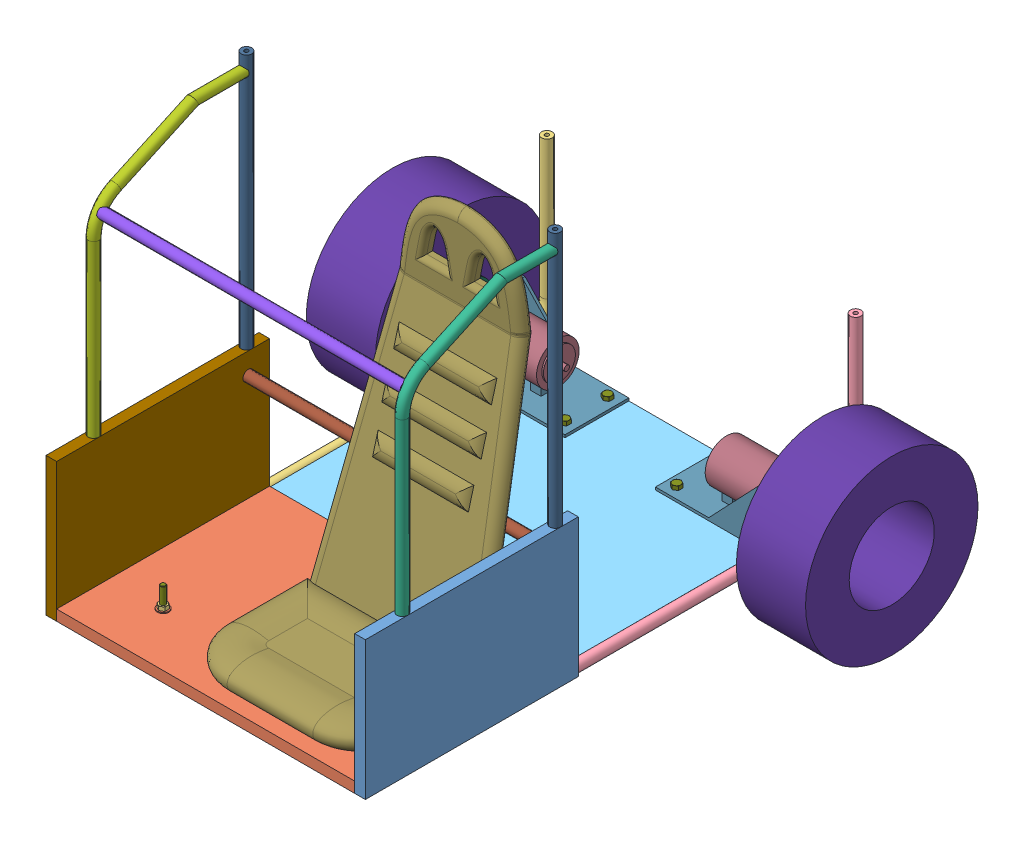
SolidWorks assembly MC (1), configuration Default. Lengths in mm.
Overall size (1191.26 1083.62 1343.85).
100 component instances, 21 part files, 123 mates.
Components (placement in the parent):
- SPL-1: SPL [Default] at (646.5449 178.7927 -996.551) size (25.4 330.2 508)
- BP-1: BP [Default] at (111.0665 -124.6065 -917.4807) size (711.2 25.4 508)
- BBR-2: BBR [Default] at (-77.3551 -47.0728 -1647.3326) x (-1 0 0) z (0 -1 0) size (25.4 687.13 407.73)
- BBL-1: BBL [Default] at (659.2449 -47.0728 -1647.3326) x (-1 0 0) z (0 -1 0) size (25.4 687.13 407.73)
- BC-1: BC [Default] at (357.2961 -116.9228 -1647.3326) x (-1 0 0) z (0 0 -1) size (723.9 12.7 609.6)
- FTL-1: FTL [Default] at (659.245 611.9935 -719.4116) x (0 -0.899323 -0.437285) z (-1 0 -0.000001) size (433.75 589.6 27.41)
- FTR-1: FTR [Default] at (-77.355 611.9935 -719.4116) x (0 -0.899323 -0.437285) z (-1 0 -0.000001) size (433.75 589.6 27.38)
- TC-1: TC [Default] at (652.8949 660.2535 -644.2461) x (0 -0.542655 -0.839955) z (-1 0 -0.000001) size (25.4 25.4 723.9)
- SPR-1: SPR [Default] at (-90.0551 178.7927 -996.551) size (25.4 330.2 508)
- BT-1: BT [Default] at (-77.3551 205.5935 -995.2506) x (0.000001 0 -1) z (1 0 0.000001) size (25.4 609.6 25.4)
- BT-2: BT [Default] at (659.2449 205.5935 -995.2506) x (0.000001 0 -1) z (1 0 0.000001) size (25.4 609.6 25.4)
- FB-1: FB [Default] at (-71.0051 154.7935 -986.9326) x (1 0 0) z (0 0.990518 0.137381) size (723.9 25.4 25.4)
- seat-1: seat [Default] at (418.0013 -99.2065 -848.8249) size (437.03 835.23 478.09)
- EA1-1: EA1 [Default] at (125.7912 -160.5315 -1631.3403) x (0 0 1) z (-1 0 0) size (411.48 411.48 487.68)
  - EB1-1: EB1 [Default] at (60.2077 126.1588 196.7963) size (101.6 101.6 238.25)
  - EP1-1: EP1 [Default] at (60.2077 56.3088 69.7963) x (0 0 1) z (-1 0 0) size (254 133.35 152.4)
  - EA2-1: EA2 [Default] at (45.9187 58.6487 138.5565) size (411.48 411.48 213.36)
    - EP2-1: EP2 [Default] at (14.289 67.5101 114.1198) size (127 127 48.26)
    - hex bolt_ai-1: hex bolt_ai [HBOLT 0.4375-20x1.375x1.125-N] at (-36.511 67.5101 106.0934) x (0 0 1) z (-0.866025 -0.5 0) size (42.95 18.33 15.88)
    - hex bolt_ai-2: hex bolt_ai [HBOLT 0.4375-20x1.375x1.125-N] at (14.289 118.3101 106.0934) x (0 0 1) z (0 -1 0) size (42.95 18.33 15.88)
    - hex bolt_ai-3: hex bolt_ai [HBOLT 0.4375-20x1.375x1.125-N] at (14.289 16.7101 106.0934) x (0 0 1) z (-0.866025 0.5 0) size (42.95 18.33 15.88)
    - hex bolt_ai-4: hex bolt_ai [HBOLT 0.4375-20x1.375x1.125-N] at (65.089 67.5101 106.0934) x (0 0 1) z (-0.866025 0.5 0) size (42.95 18.33 15.88)
    - EB2-1: EB2 [Default] at (14.289 67.5101 129.9948) x (-1 0 0) z (0 0 -1) size (411.48 411.48 165.1)
    - flat washer type a wide_ai-1: flat washer type a wide_ai [Preferred Wide FW 0.4375] at (-36.511 67.5101 132.103) x (0 0 1) z (-0.923728 -0.383049 0) size (2.11 31.75 31.75)
    - flat washer type a wide_ai-2: flat washer type a wide_ai [Preferred Wide FW 0.4375] at (14.289 118.3101 132.103) x (0 0 1) z (1 0 0) size (2.11 31.75 31.75)
    - flat washer type a wide_ai-3: flat washer type a wide_ai [Preferred Wide FW 0.4375] at (14.289 16.7101 132.103) x (0 0 1) z (1 0 0) size (2.11 31.75 31.75)
    - flat washer type a wide_ai-4: flat washer type a wide_ai [Preferred Wide FW 0.4375] at (65.089 67.5101 132.103) x (0 0 1) z (1 0 0) size (2.11 31.75 31.75)
    - hex thick nut_ai-1: hex thick nut_ai [HTNUT 0.4375-14-D-N] at (14.289 16.7101 143.8632) x (0.055202 -0.998475 0) z (0 0 1) size (17.48 20.18 11.76)
    - hex thick nut_ai-2: hex thick nut_ai [HTNUT 0.4375-14-D-N] at (-36.511 67.5101 143.8632) x (0.547044 -0.837104 0) z (0 0 1) size (17.48 20.18 11.76)
    - hex thick nut_ai-3: hex thick nut_ai [HTNUT 0.4375-14-D-N] at (65.089 67.5101 143.8632) x (-0.982324 -0.18719 0) z (0 0 1) size (17.48 20.18 11.76)
    - hex thick nut_ai-4: hex thick nut_ai [HTNUT 0.4375-14-D-N] at (14.289 118.3101 143.8632) x (0.055202 -0.998475 0) z (0 0 1) size (17.48 20.18 11.76)
  - hex bolt_ai-8: hex bolt_ai [HBOLT 0.3125-18x1.375x0.875-N] at (17.0277 169.3388 215.4653) x (0 0 -1) z (0 1 0) size (40.89 14.66 12.7)
  - hex bolt_ai-9: hex bolt_ai [HBOLT 0.3125-18x1.375x0.875-N] at (103.3877 169.3388 215.4653) x (0 0 -1) z (0.866025 -0.5 0) size (40.89 14.66 12.7)
  - hex bolt_ai-10: hex bolt_ai [HBOLT 0.3125-18x1.375x0.875-N] at (103.3877 82.9788 215.4653) x (0 0 -1) z (0.866025 0.5 0) size (40.89 14.66 12.7)
  - hex bolt_ai-11: hex bolt_ai [HBOLT 0.3125-18x1.375x0.875-N] at (17.0277 82.9788 215.4653) x (0 0 -1) z (-0.866025 -0.5 0) size (40.89 14.66 12.7)
  - flat washer type a narrow_ai-1: flat washer type a narrow_ai [Preferred Narrow FW 0.3125] at (17.0277 169.3388 190.4463) x (0 0 1) z (-1 0 0) size (1.65 17.48 17.48)
  - flat washer type a narrow_ai-2: flat washer type a narrow_ai [Preferred Narrow FW 0.3125] at (103.3877 82.9788 190.4463) x (0 0 1) z (-1 0 0) size (1.65 17.48 17.48)
  - flat washer type a narrow_ai-3: flat washer type a narrow_ai [Preferred Narrow FW 0.3125] at (17.0277 82.9788 188.7953) x (0 0 -1) z (1 0 0) size (1.65 17.48 17.48)
  - flat washer type a narrow_ai-4: flat washer type a narrow_ai [Preferred Narrow FW 0.3125] at (103.3877 169.3388 188.7953) x (0 0 -1) z (0.923728 0.383049 0) size (1.65 17.48 17.48)
  - hex thick nut_ai-1: hex thick nut_ai [HTNUT 0.3125-18-D-N] at (103.3877 169.3388 188.7953) x (0.866025 0.5 0) z (0 0 1) size (12.7 14.66 8.53)
  - hex thick nut_ai-2: hex thick nut_ai [HTNUT 0.3125-18-D-N] at (17.0277 82.9788 180.2609) x (-0.866025 0.5 0) z (0 0 -1) size (12.7 14.66 8.53)
  - hex thick nut_ai-3: hex thick nut_ai [HTNUT 0.3125-18-D-N] at (103.3877 82.9788 181.9119) x (-0.866025 -0.5 0) z (0 0 -1) size (12.7 14.66 8.53)
  - hex thick nut_ai-4: hex thick nut_ai [HTNUT 0.3125-18-D-N] at (17.0277 169.3388 180.2609) x (-0.866025 -0.5 0) z (0 0 -1) size (12.7 14.66 8.53)
- EA1-2: EA1 [Default] at (456.0986 -160.5315 -1510.9249) x (0 0 -1) z (1 0 0) size (411.48 411.48 487.68)
  - EB1-1: EB1 [Default] at (60.2077 126.1588 196.7963) size (101.6 101.6 238.25)
  - EP1-1: EP1 [Default] at (60.2077 56.3088 69.7963) x (0 0 1) z (-1 0 0) size (254 133.35 152.4)
  - EA2-1: EA2 [Default] at (45.9187 58.6487 138.5565) size (411.48 411.48 213.36)
    - EP2-1: EP2 [Default] at (14.289 67.5101 114.1198) size (127 127 48.26)
    - hex bolt_ai-1: hex bolt_ai [HBOLT 0.4375-20x1.375x1.125-N] at (-36.511 67.5101 106.0934) x (0 0 1) z (-0.866025 -0.5 0) size (42.95 18.33 15.88)
    - hex bolt_ai-2: hex bolt_ai [HBOLT 0.4375-20x1.375x1.125-N] at (14.289 118.3101 106.0934) x (0 0 1) z (0 -1 0) size (42.95 18.33 15.88)
    - hex bolt_ai-3: hex bolt_ai [HBOLT 0.4375-20x1.375x1.125-N] at (14.289 16.7101 106.0934) x (0 0 1) z (-0.866025 0.5 0) size (42.95 18.33 15.88)
    - hex bolt_ai-4: hex bolt_ai [HBOLT 0.4375-20x1.375x1.125-N] at (65.089 67.5101 106.0934) x (0 0 1) z (-0.866025 0.5 0) size (42.95 18.33 15.88)
    - EB2-1: EB2 [Default] at (14.289 67.5101 129.9948) x (-1 0 0) z (0 0 -1) size (411.48 411.48 165.1)
    - flat washer type a wide_ai-1: flat washer type a wide_ai [Preferred Wide FW 0.4375] at (-36.511 67.5101 132.103) x (0 0 1) z (-0.923728 -0.383049 0) size (2.11 31.75 31.75)
    - flat washer type a wide_ai-2: flat washer type a wide_ai [Preferred Wide FW 0.4375] at (14.289 118.3101 132.103) x (0 0 1) z (1 0 0) size (2.11 31.75 31.75)
    - flat washer type a wide_ai-3: flat washer type a wide_ai [Preferred Wide FW 0.4375] at (14.289 16.7101 132.103) x (0 0 1) z (1 0 0) size (2.11 31.75 31.75)
    - flat washer type a wide_ai-4: flat washer type a wide_ai [Preferred Wide FW 0.4375] at (65.089 67.5101 132.103) x (0 0 1) z (1 0 0) size (2.11 31.75 31.75)
    - hex thick nut_ai-1: hex thick nut_ai [HTNUT 0.4375-14-D-N] at (14.289 16.7101 143.8632) x (0.055202 -0.998475 0) z (0 0 1) size (17.48 20.18 11.76)
    - hex thick nut_ai-2: hex thick nut_ai [HTNUT 0.4375-14-D-N] at (-36.511 67.5101 143.8632) x (0.547044 -0.837104 0) z (0 0 1) size (17.48 20.18 11.76)
    - hex thick nut_ai-3: hex thick nut_ai [HTNUT 0.4375-14-D-N] at (65.089 67.5101 143.8632) x (-0.982324 -0.18719 0) z (0 0 1) size (17.48 20.18 11.76)
    - hex thick nut_ai-4: hex thick nut_ai [HTNUT 0.4375-14-D-N] at (14.289 118.3101 143.8632) x (0.055202 -0.998475 0) z (0 0 1) size (17.48 20.18 11.76)
  - hex bolt_ai-8: hex bolt_ai [HBOLT 0.3125-18x1.375x0.875-N] at (17.0277 169.3388 215.4653) x (0 0 -1) z (0 1 0) size (40.89 14.66 12.7)
  - hex bolt_ai-9: hex bolt_ai [HBOLT 0.3125-18x1.375x0.875-N] at (103.3877 169.3388 215.4653) x (0 0 -1) z (0.866025 -0.5 0) size (40.89 14.66 12.7)
  - hex bolt_ai-10: hex bolt_ai [HBOLT 0.3125-18x1.375x0.875-N] at (103.3877 82.9788 215.4653) x (0 0 -1) z (0.866025 0.5 0) size (40.89 14.66 12.7)
  - hex bolt_ai-11: hex bolt_ai [HBOLT 0.3125-18x1.375x0.875-N] at (17.0277 82.9788 215.4653) x (0 0 -1) z (-0.866025 -0.5 0) size (40.89 14.66 12.7)
  - flat washer type a narrow_ai-1: flat washer type a narrow_ai [Preferred Narrow FW 0.3125] at (17.0277 169.3388 190.4463) x (0 0 1) z (-1 0 0) size (1.65 17.48 17.48)
  - flat washer type a narrow_ai-2: flat washer type a narrow_ai [Preferred Narrow FW 0.3125] at (103.3877 82.9788 190.4463) x (0 0 1) z (-1 0 0) size (1.65 17.48 17.48)
  - flat washer type a narrow_ai-3: flat washer type a narrow_ai [Preferred Narrow FW 0.3125] at (17.0277 82.9788 188.7953) x (0 0 -1) z (1 0 0) size (1.65 17.48 17.48)
  - flat washer type a narrow_ai-4: flat washer type a narrow_ai [Preferred Narrow FW 0.3125] at (103.3877 169.3388 188.7953) x (0 0 -1) z (0.923728 0.383049 0) size (1.65 17.48 17.48)
  - hex thick nut_ai-1: hex thick nut_ai [HTNUT 0.3125-18-D-N] at (103.3877 169.3388 188.7953) x (0.866025 0.5 0) z (0 0 1) size (12.7 14.66 8.53)
  - hex thick nut_ai-2: hex thick nut_ai [HTNUT 0.3125-18-D-N] at (17.0277 82.9788 180.2609) x (-0.866025 0.5 0) z (0 0 -1) size (12.7 14.66 8.53)
  - hex thick nut_ai-3: hex thick nut_ai [HTNUT 0.3125-18-D-N] at (103.3877 82.9788 181.9119) x (-0.866025 -0.5 0) z (0 0 -1) size (12.7 14.66 8.53)
  - hex thick nut_ai-4: hex thick nut_ai [HTNUT 0.3125-18-D-N] at (17.0277 169.3388 180.2609) x (-0.866025 -0.5 0) z (0 0 -1) size (12.7 14.66 8.53)
- hex bolt_ai-1: hex bolt_ai [HBOLT 0.5000-13x1.375x1.25-N] at (157.5949 -88.6272 -1621.9326) x (0 -1 0) z (-1 0 0) size (44.17 22 19.05)
- hex bolt_ai-2: hex bolt_ai [HBOLT 0.5000-13x1.375x1.25-N] at (157.5949 -88.6272 -1520.3326) x (0 -1 0) z (0.5 0 -0.866025) size (44.17 22 19.05)
- hex bolt_ai-3: hex bolt_ai [HBOLT 0.5000-13x1.375x1.25-N] at (424.2949 -88.6272 -1520.3326) x (0 -1 0) z (1 0 0) size (44.17 22 19.05)
- hex bolt_ai-4: hex bolt_ai [HBOLT 0.5000-13x1.375x1.25-N] at (602.0949 -88.6272 -1621.9326) x (0 -1 0) z (-0.5 0 -0.866025) size (44.17 22 19.05)
- hex bolt_ai-5: hex bolt_ai [HBOLT 0.5000-13x1.375x1.25-N] at (424.2949 -88.6272 -1621.9326) x (0 -1 0) z (0.5 0 -0.866025) size (44.17 22 19.05)
- hex bolt_ai-6: hex bolt_ai [HBOLT 0.5000-13x1.375x1.25-N] at (602.0949 -88.6272 -1520.3326) x (0 -1 0) z (-0.5 0 0.866025) size (44.17 22 19.05)
- hex bolt_ai-7: hex bolt_ai [HBOLT 0.5000-13x1.375x1.25-N] at (-20.2051 -88.6272 -1621.9326) x (0 -1 0) z (-1 0 0) size (44.17 22 19.05)
- hex bolt_ai-8: hex bolt_ai [HBOLT 0.5000-13x1.375x1.25-N] at (-20.2051 -88.6272 -1520.3326) x (0 -1 0) z (1 0 0) size (44.17 22 19.05)
- flat washer type a wide_ai-1: flat washer type a wide_ai [Preferred Wide FW 0.5] at (157.5949 -119.6914 -1520.3326) x (0 -1 0) z (0.546944 0 -0.837169) size (2.77 34.92 34.92)
- flat washer type a wide_ai-2: flat washer type a wide_ai [Preferred Wide FW 0.5] at (157.5949 -119.6914 -1621.9326) x (0 -1 0) z (0.967366 0 0.253384) size (2.77 34.92 34.92)
- flat washer type a wide_ai-3: flat washer type a wide_ai [Preferred Wide FW 0.5] at (424.2949 -119.6914 -1621.9326) x (0 -1 0) z (-0.558017 0 -0.829829) size (2.77 34.92 34.92)
- flat washer type a wide_ai-4: flat washer type a wide_ai [Preferred Wide FW 0.5] at (-20.2051 -119.6914 -1520.3326) x (0 -1 0) z (0.590888 0 -0.806754) size (2.77 34.92 34.92)
- flat washer type a wide_ai-5: flat washer type a wide_ai [Preferred Wide FW 0.5] at (602.0949 -119.6914 -1520.3326) x (0 -1 0) z (0.610265 0 -0.792197) size (2.77 34.92 34.92)
- flat washer type a wide_ai-6: flat washer type a wide_ai [Preferred Wide FW 0.5] at (424.2949 -119.6914 -1520.3326) x (0 -1 0) z (0.837672 0 -0.546174) size (2.77 34.92 34.92)
- flat washer type a wide_ai-7: flat washer type a wide_ai [Preferred Wide FW 0.5] at (602.0949 -119.6914 -1621.9326) x (0 -1 0) z (0.97172 0 -0.236136) size (2.77 34.92 34.92)
- flat washer type a wide_ai-8: flat washer type a wide_ai [Preferred Wide FW 0.5] at (-20.2051 -119.6914 -1621.9326) x (0 -1 0) z (0.345214 0 -0.938524) size (2.77 34.92 34.92)
- hex nut_ai-1: hex nut_ai [HNUT 0.5000-13-D-N] at (157.5949 -131.0706 -1520.3326) x (-0.5 0 -0.866025) z (0 -1 0) size (19.05 22 11.38)
- hex nut_ai-2: hex nut_ai [HNUT 0.5000-13-D-N] at (-20.2051 -131.0706 -1621.9326) x (-0.866025 0 -0.5) z (0 -1 0) size (19.05 22 11.38)
- hex nut_ai-3: hex nut_ai [HNUT 0.5000-13-D-N] at (-20.2051 -131.0706 -1520.3326) x (0 0 -1) z (0 -1 0) size (19.05 22 11.38)
- hex nut_ai-4: hex nut_ai [HNUT 0.5000-13-D-N] at (157.5949 -131.0706 -1621.9326) x (0 0 -1) z (0 -1 0) size (19.05 22 11.38)
- hex nut_ai-5: hex nut_ai [HNUT 0.5000-13-D-N] at (424.2949 -131.0706 -1520.3326) x (0 0 1) z (0 -1 0) size (19.05 22 11.38)
- hex nut_ai-6: hex nut_ai [HNUT 0.5000-13-D-N] at (424.2949 -131.0706 -1621.9326) x (-0.866025 0 0.5) z (0 -1 0) size (19.05 22 11.38)
- hex nut_ai-8: hex nut_ai [HNUT 0.5000-13-D-N] at (602.0949 -131.0706 -1520.3326) x (-0.866025 0 -0.5) z (0 -1 0) size (19.05 22 11.38)
- hex nut_ai-9: hex nut_ai [HNUT 0.5000-13-D-N] at (602.0949 -131.0706 -1621.9326) x (-0.866025 0 -0.5) z (0 -1 0) size (19.05 22 11.38)
- hex bolt_ai-11: hex bolt_ai [HBOLT 0.5000-13x3x1.25-N] at (62.3449 -133.8521 -656.7326) x (0 1 0) z (-0.5 0 0.866025) size (85.45 22 19.05)
- flat washer type a narrow_ai-1: flat washer type a narrow_ai [Preferred Narrow FW 0.5] at (62.3449 -99.2065 -656.7326) x (0 -1 0) z (0 0 1) size (2.41 26.97 26.97)
- hex nut_ai-10: hex nut_ai [HNUT 0.5000-13-D-N] at (62.3449 -87.8273 -656.7326) x (1 0 0) z (0 1 0) size (19.05 22 11.38)
Mates (geometry in assembly coordinates):
- Coincident29: coincident: plane of SPL-1 through (671.9449 205.5935 -1037.7326) normal (0 0 -1); plane of BBL-1 through (659.2449 -111.9065 -1037.7326) normal (0 0 1)
- Tangent6: tangent: plane of SPL-1 through (671.9449 178.7927 -996.551) normal (1 0 0); cylinder of BBL-1 through (659.2449 -111.9065 -1037.7326) axis (0 0 -1) radius 12.7
- Tangent7: tangent: plane of SPL-1 through (671.9449 -124.6065 -529.7326) normal (0 -1 0); cylinder of BBL-1 through (659.2449 -111.9065 -1037.7326) axis (0 0 -1) radius 12.7
- Coincident32: coincident: plane of BP-1 through (-64.6551 -99.2065 -1037.7326) normal (0 0 -1); plane of BC-1 through (652.8949 -104.2228 -1037.7326) normal (0 0 1)
- Coincident34: coincident: plane of BBR-2 through (-71.0051 -104.2228 -1037.7326) normal (0 -1 0); plane of BC-1 through (357.2961 -104.2228 -1647.3326) normal (0 1 0)
- Tangent9: tangent: plane of SPL-1 through (671.9449 178.7927 -996.551) normal (1 0 0); cylinder of BBL-1 through (659.2449 283.1272 -1712.1664) axis (0 -1 0) radius 12.7
- Tangent10: tangent: plane of SPL-1 through (671.9449 178.7927 -996.551) normal (1 0 0); cylinder of FTL-1 through (659.2449 205.5935 -630.5357) axis (0 1 0) radius 12.7
- Coincident46: coincident: plane of SPL-1 through (646.5449 178.7927 -996.551) normal (-1 0 0); plane of BP-1 through (646.5449 -99.2065 -1037.7326) normal (1 0 0)
- Coincident48: coincident: plane of SPL-1 through (671.9449 -124.6065 -529.7326) normal (0 -1 0); plane of BP-1 through (111.0665 -124.6065 -917.4807) normal (0 -1 0)
- Parallel1: parallel: plane of BP-1 through (111.0665 -124.6065 -917.4807) normal (0 -1 0); plane of BC-1 through (357.2961 -116.9228 -1647.3326) normal (0 -1 0)
- Distance1: distance = 101.6 mm: cylinder of FTL-1 through (659.2449 205.5935 -630.5357) axis (0 1 0) radius 12.7; line of SPL-1 through (646.5449 205.5935 -529.7326) axis (0 -1 0)
- Coincident53: coincident: plane of FTR-1 through (-71.0051 660.2535 -644.2465) normal (1 0 0.000001); plane of TC-1 through (-71.0051 660.2535 -644.2465) normal (-1 0 -0.000001)
- Coincident55: coincident: plane of FTL-1 through (652.8949 660.2535 -644.2465) normal (-1 0 -0.000001); circle of TC-1
- Coincident56: coincident: plane of SPL-1 through (671.9449 205.5935 -1037.7326) normal (0 0 -1); plane of BP-1 through (-64.6551 -99.2065 -1037.7326) normal (0 0 -1)
- Coincident60: coincident: plane of SPL-1 through (671.9449 205.5935 -1037.7326) normal (0 0 -1); plane of BP-1 through (-64.6551 -99.2065 -1037.7326) normal (0 0 -1)
- Coincident61: coincident: plane of BP-1 through (111.0665 -124.6065 -917.4807) normal (0 -1 0); plane of SPR-1 through (-64.6551 -124.6065 -529.7326) normal (0 -1 0)
- Coincident62: coincident: plane of BP-1 through (-64.6551 -99.2065 -1037.7326) normal (-1 0 0); plane of SPR-1 through (-64.6551 178.7927 -996.551) normal (1 0 0)
- Coincident63: coincident: plane of BP-1 through (-64.6551 -99.2065 -1037.7326) normal (0 0 -1); plane of SPR-1 through (-64.6551 205.5935 -1037.7326) normal (0 0 -1)
- Tangent20: tangent: cylinder of BBR-2 through (-77.3551 -111.9065 -1037.7326) axis (0 0 -1) radius 12.7; plane of SPR-1 through (-90.0551 178.7927 -996.551) normal (-1 0 0)
- Tangent21: tangent: cylinder of BBR-2 through (-77.3551 -111.9065 -1037.7326) axis (0 0 -1) radius 12.7; plane of SPR-1 through (-64.6551 -124.6065 -529.7326) normal (0 -1 0)
- Tangent24: tangent: cylinder of BBR-2 through (-77.3551 -111.9065 -1037.7326) axis (0 0 -1) radius 12.7; plane of SPR-1 through (-64.6551 -124.6065 -529.7326) normal (0 -1 0)
- Coincident67: coincident: plane of BBR-2 through (-77.3551 -111.9065 -1037.7326) normal (0 0 1); plane of SPR-1 through (-64.6551 205.5935 -1037.7326) normal (0 0 -1)
- Parallel2: parallel: cylinder of BBR-2 through (-77.3551 283.1272 -1712.1664) axis (0 -1 0) radius 12.7; line of SPR-1 through (-64.6551 -124.6065 -1037.7326) axis (0 1 0)
- Coincident69: coincident: plane of SPR-1 through (-64.6551 205.5935 -529.7326) normal (0 1 0); plane of BT-1 through (-77.3551 205.5935 -995.2506) normal (0 -1 0)
- Coincident70: coincident: plane of SPL-1 through (671.9449 205.5935 -529.7326) normal (0 1 0); plane of BT-2 through (659.2449 205.5935 -995.2506) normal (0 -1 0)
- Coincident73: coincident: plane of SPR-1 through (-64.6551 205.5935 -529.7326) normal (0 1 0); plane of BT-1 through (-77.3551 205.5935 -995.2506) normal (0 -1 0)
- Tangent34: tangent: plane of SPR-1 through (-90.0551 178.7927 -996.551) normal (-1 0 0); cylinder of BT-1 through (-77.3551 815.1935 -995.2506) axis (0 -1 0) radius 12.7
- Tangent36: tangent: plane of SPL-1 through (671.9449 178.7927 -996.551) normal (1 0 0); cylinder of BT-2 through (659.2449 815.1935 -995.2506) axis (0 -1 0) radius 12.7
- Coincident74: coincident: plane of SPL-1 through (652.8949 154.7935 -986.9326) normal (-1 0 0); plane of FB-1 through (652.8949 154.7935 -986.9326) normal (1 0 0)
- Coincident75: coincident: plane of SPR-1 through (-71.0051 154.7935 -986.9326) normal (1 0 0); plane of FB-1 through (-71.0051 154.7935 -986.9326) normal (-1 0 0)
- Concentric1: concentric: circle of SPL-1; circle of FB-1
- Coincident77: coincident: plane of SPR-1 through (-71.0051 154.7935 -986.9326) normal (1 0 0); circle of FB-1
- Concentric2: concentric: circle of SPR-1; circle of FB-1
- Coincident81: coincident: plane of BP-1 through (111.0665 -99.2065 -917.4807) normal (0 1 0); plane of seat-1 through (633.9013 -99.2065 -833.6366) normal (0 -1 0)
- Coincident82: coincident: plane of FTR-1 through (-77.3551 205.5935 -630.5357) normal (0 -1 0); plane of SPR-1 through (-64.6551 205.5935 -529.7326) normal (0 1 0)
- Coincident83: coincident: plane of SPL-1 through (671.9449 205.5935 -529.7326) normal (0 1 0); plane of FTL-1 through (659.2449 205.5935 -630.5357) normal (0 -1 0)
- Coincident84: coincident: plane of BC-1 through (357.2961 -104.2228 -1647.3326) normal (0 1 0); plane of EA1-1/EP1-1 through (55.9949 -104.2228 -1571.1326) normal (0 -1 0)
- Concentric3: concentric: circle of BC-1; circle of EA1-1/EP1-1
- Concentric5: concentric: circle of BC-1; circle of EA1-1/EP1-1
- Coincident89: coincident: plane of BC-1 through (357.2961 -104.2228 -1647.3326) normal (0 1 0); plane of EA1-2/EP1-1 through (525.8949 -104.2228 -1571.1326) normal (0 -1 0)
- Concentric6: concentric: circle of BC-1; circle of EA1-2/EP1-1
- Concentric7: concentric: circle of BC-1; circle of EA1-2/EP1-1
- Concentric8: concentric: cylinder of EA1-1/EP1-1 through (157.5949 -123.2728 -1520.3326) axis (0 1 0) radius 6.35; cylinder of hex bolt_ai-2 through (157.5949 -88.6272 -1520.3326) axis (0 1 0) radius 6.35
- Coincident92: coincident: plane of EA1-1/EP1-1 through (55.9949 -97.8728 -1571.1326) normal (0 1 0); plane of hex bolt_ai-2 through (148.0699 -97.8728 -1525.8319) normal (0 -1 0)
- Parallel8: parallel: plane of EA1-1/EP1-1 through (182.9949 -97.8728 -1494.9326) normal (1 0 0); plane of hex bolt_ai-2 through (167.1199 -97.8728 -1514.8333) normal (1 0 0)
- Concentric9: concentric: cylinder of hex bolt_ai-2 through (157.5949 -88.6272 -1520.3326) axis (0 1 0) radius 6.35; cylinder of flat washer type a wide_ai-1 through (157.5949 -84.7664 -1520.3326) axis (0 1 0) radius 7.1374
- Coincident94: coincident: plane of BC-1 through (357.2961 -116.9228 -1647.3326) normal (0 -1 0); plane of flat washer type a wide_ai-1 through (142.9759 -116.9228 -1529.8836) normal (0 1 0)
- Concentric10: concentric: cylinder of hex bolt_ai-2 through (157.5949 -88.6272 -1520.3326) axis (0 1 0) radius 6.35; cylinder of hex nut_ai-1 through (157.5949 -119.6914 -1520.3326) axis (0 -1 0) radius 5.3581
- Coincident95: coincident: plane of flat washer type a wide_ai-1 through (151.6197 -119.6914 -1524.2364) normal (0 -1 0); plane of hex nut_ai-1 through (167.1199 -119.6914 -1525.8319) normal (0 1 0)
- Parallel9: parallel: plane of EA1-1/EP1-1 through (182.9949 -97.8728 -1494.9326) normal (1 0 0); plane of hex nut_ai-1 through (167.1199 -119.6914 -1525.8319) normal (1 0 0)
- Concentric11: concentric: cylinder of EA1-1/EP1-1 through (157.5949 -123.2728 -1621.9326) axis (0 1 0) radius 6.35; cylinder of hex bolt_ai-1 through (157.5949 -88.6272 -1621.9326) axis (0 1 0) radius 6.35
- Coincident97: coincident: plane of EA1-1/EP1-1 through (55.9949 -97.8728 -1571.1326) normal (0 1 0); plane of hex bolt_ai-1 through (157.5949 -97.8728 -1610.9341) normal (0 -1 0)
- Parallel10: parallel: plane of EA1-1/EP1-1 through (182.9949 -97.8728 -1494.9326) normal (1 0 0); plane of hex bolt_ai-1 through (167.1199 -97.8728 -1616.4333) normal (1 0 0)
- Concentric12: concentric: cylinder of EA1-2/EP1-1 through (424.2949 -123.2728 -1520.3326) axis (0 1 0) radius 6.35; cylinder of hex bolt_ai-3 through (424.2949 -88.6272 -1520.3326) axis (0 1 0) radius 6.35
- Coincident99: coincident: plane of EA1-2/EP1-1 through (525.8949 -97.8728 -1571.1326) normal (0 1 0); plane of hex bolt_ai-3 through (424.2949 -97.8728 -1531.3311) normal (0 -1 0)
- Parallel11: parallel: plane of EA1-2/EP1-1 through (398.8949 -97.8728 -1647.3326) normal (-1 0 0); plane of hex bolt_ai-3 through (433.8199 -97.8728 -1525.8319) normal (1 0 0)
- Concentric13: concentric: cylinder of BC-1 through (424.2949 -116.9228 -1621.9326) axis (0 1 0) radius 6.35; cylinder of hex bolt_ai-5 through (424.2949 -88.6272 -1621.9326) axis (0 1 0) radius 6.35
- Coincident101: coincident: plane of EA1-2/EP1-1 through (525.8949 -97.8728 -1571.1326) normal (0 1 0); plane of hex bolt_ai-5 through (414.7699 -97.8728 -1627.4319) normal (0 -1 0)
- Concentric14: concentric: cylinder of EA1-1/EP1-1 through (-20.2051 -123.2728 -1520.3326) axis (0 1 0) radius 6.35; cylinder of hex bolt_ai-8 through (-20.2051 -88.6272 -1520.3326) axis (0 1 0) radius 6.35
- Coincident102: coincident: plane of EA1-1/EP1-1 through (55.9949 -97.8728 -1571.1326) normal (0 1 0); plane of hex bolt_ai-8 through (-20.2051 -97.8728 -1531.3311) normal (0 -1 0)
- Parallel12: parallel: plane of EA1-1/EP1-1 through (182.9949 -97.8728 -1494.9326) normal (1 0 0); plane of hex bolt_ai-8 through (-10.6801 -97.8728 -1525.8319) normal (1 0 0)
- Concentric15: concentric: cylinder of EA1-1/EP1-1 through (-20.2051 -123.2728 -1621.9326) axis (0 1 0) radius 6.35; cylinder of hex bolt_ai-7 through (-20.2051 -88.6272 -1621.9326) axis (0 1 0) radius 6.35
- Coincident104: coincident: plane of EA1-1/EP1-1 through (55.9949 -97.8728 -1571.1326) normal (0 1 0); plane of hex bolt_ai-7 through (-20.2051 -97.8728 -1610.9341) normal (0 -1 0)
- Parallel13: parallel: plane of EA1-1/EP1-1 through (182.9949 -97.8728 -1494.9326) normal (1 0 0); plane of hex bolt_ai-7 through (-10.6801 -97.8728 -1616.4333) normal (1 0 0)
- Concentric16: concentric: cylinder of EA1-2/EP1-1 through (602.0949 -123.2728 -1621.9326) axis (0 1 0) radius 6.35; cylinder of hex bolt_ai-4 through (602.0949 -88.6272 -1621.9326) axis (0 1 0) radius 6.35
- Coincident106: coincident: plane of EA1-2/EP1-1 through (525.8949 -97.8728 -1571.1326) normal (0 1 0); plane of hex bolt_ai-4 through (592.5699 -97.8728 -1616.4333) normal (0 -1 0)
- Parallel14: parallel: plane of EA1-2/EP1-1 through (398.8949 -97.8728 -1647.3326) normal (-1 0 0); plane of hex bolt_ai-4 through (592.5699 -97.8728 -1616.4333) normal (-1 0 0)
- Concentric17: concentric: cylinder of EA1-2/EP1-1 through (602.0949 -123.2728 -1520.3326) axis (0 1 0) radius 6.35; cylinder of hex bolt_ai-6 through (602.0949 -88.6272 -1520.3326) axis (0 1 0) radius 6.35
- Coincident108: coincident: plane of EA1-2/EP1-1 through (525.8949 -97.8728 -1571.1326) normal (0 1 0); plane of hex bolt_ai-6 through (611.6199 -97.8728 -1514.8333) normal (0 -1 0)
- Parallel15: parallel: plane of EA1-2/EP1-1 through (398.8949 -97.8728 -1647.3326) normal (-1 0 0); plane of hex bolt_ai-6 through (592.5699 -97.8728 -1525.8319) normal (-1 0 0)
- Parallel16: parallel: plane of EA1-2/EP1-1 through (398.8949 -97.8728 -1647.3326) normal (-1 0 0); plane of hex bolt_ai-5 through (414.7699 -97.8728 -1616.4333) normal (-1 0 0)
- Concentric18: concentric: cylinder of hex bolt_ai-1 through (157.5949 -88.6272 -1621.9326) axis (0 1 0) radius 6.35; cylinder of flat washer type a wide_ai-2 through (157.5949 -84.7664 -1621.9326) axis (0 1 0) radius 7.1374
- Concentric19: concentric: cylinder of hex bolt_ai-8 through (-20.2051 -88.6272 -1520.3326) axis (0 1 0) radius 6.35; cylinder of flat washer type a wide_ai-4 through (-20.2051 -84.7664 -1520.3326) axis (0 1 0) radius 7.1374
- Concentric20: concentric: cylinder of hex bolt_ai-7 through (-20.2051 -88.6272 -1621.9326) axis (0 1 0) radius 6.35; cylinder of flat washer type a wide_ai-8 through (-20.2051 -84.7664 -1621.9326) axis (0 1 0) radius 7.1374
- Concentric21: concentric: cylinder of hex bolt_ai-5 through (424.2949 -88.6272 -1621.9326) axis (0 1 0) radius 6.35; cylinder of flat washer type a wide_ai-3 through (424.2949 -84.7664 -1621.9326) axis (0 1 0) radius 7.1374
- Concentric22: concentric: cylinder of hex bolt_ai-3 through (424.2949 -88.6272 -1520.3326) axis (0 1 0) radius 6.35; cylinder of flat washer type a wide_ai-6 through (424.2949 -84.7664 -1520.3326) axis (0 1 0) radius 7.1374
- Concentric23: concentric: cylinder of hex bolt_ai-6 through (602.0949 -88.6272 -1520.3326) axis (0 1 0) radius 6.35; cylinder of flat washer type a wide_ai-5 through (602.0949 -84.7664 -1520.3326) axis (0 1 0) radius 7.1374
- Concentric24: concentric: cylinder of hex bolt_ai-4 through (602.0949 -88.6272 -1621.9326) axis (0 1 0) radius 6.35; cylinder of flat washer type a wide_ai-7 through (602.0949 -84.7664 -1621.9326) axis (0 1 0) radius 7.1374
- Coincident111: coincident: plane of BC-1 through (357.2961 -116.9228 -1647.3326) normal (0 -1 0); plane of flat washer type a wide_ai-5 through (588.2612 -116.9228 -1530.9894) normal (0 1 0)
- Coincident112: coincident: plane of BC-1 through (357.2961 -116.9228 -1647.3326) normal (0 -1 0); plane of flat washer type a wide_ai-7 through (597.9714 -116.9228 -1638.9013) normal (0 1 0)
- Coincident113: coincident: plane of BC-1 through (357.2961 -116.9228 -1647.3326) normal (0 -1 0); plane of flat washer type a wide_ai-6 through (414.7574 -116.9228 -1534.9604) normal (0 1 0)
- Coincident114: coincident: plane of BC-1 through (357.2961 -116.9228 -1647.3326) normal (0 -1 0); plane of flat washer type a wide_ai-3 through (409.804 -116.9228 -1612.1882) normal (0 1 0)
- Coincident115: coincident: plane of BC-1 through (357.2961 -116.9228 -1647.3326) normal (0 -1 0); plane of flat washer type a wide_ai-2 through (162.0196 -116.9228 -1638.8252) normal (0 1 0)
- Coincident116: coincident: plane of BC-1 through (357.2961 -116.9228 -1647.3326) normal (0 -1 0); plane of flat washer type a wide_ai-4 through (-34.293 -116.9228 -1530.651) normal (0 1 0)
- Coincident117: coincident: plane of BC-1 through (357.2961 -116.9228 -1647.3326) normal (0 -1 0); plane of flat washer type a wide_ai-8 through (-36.5941 -116.9228 -1627.9609) normal (0 1 0)
- Concentric26: concentric: cylinder of hex bolt_ai-7 through (-20.2051 -88.6272 -1621.9326) axis (0 1 0) radius 6.35; cylinder of hex nut_ai-2 through (-20.2051 -119.6914 -1621.9326) axis (0 -1 0) radius 5.3581
- Concentric27: concentric: cylinder of hex bolt_ai-8 through (-20.2051 -88.6272 -1520.3326) axis (0 1 0) radius 6.35; cylinder of hex nut_ai-3 through (-20.2051 -119.6914 -1520.3326) axis (0 -1 0) radius 5.3581
- Concentric28: concentric: cylinder of hex bolt_ai-1 through (157.5949 -88.6272 -1621.9326) axis (0 1 0) radius 6.35; cylinder of hex nut_ai-4 through (157.5949 -119.6914 -1621.9326) axis (0 -1 0) radius 5.3581
- Concentric29: concentric: cylinder of hex bolt_ai-5 through (424.2949 -88.6272 -1621.9326) axis (0 1 0) radius 6.35; cylinder of hex nut_ai-6 through (424.2949 -119.6914 -1621.9326) axis (0 -1 0) radius 5.3581
- Concentric30: concentric: cylinder of hex bolt_ai-3 through (424.2949 -88.6272 -1520.3326) axis (0 1 0) radius 6.35; cylinder of hex nut_ai-5 through (424.2949 -119.6914 -1520.3326) axis (0 -1 0) radius 5.3581
- Concentric31: concentric: cylinder of hex bolt_ai-6 through (602.0949 -88.6272 -1520.3326) axis (0 1 0) radius 6.35; cylinder of hex nut_ai-8 through (602.0949 -119.6914 -1520.3326) axis (0 -1 0) radius 5.3581
- Concentric32: concentric: cylinder of hex bolt_ai-4 through (602.0949 -88.6272 -1621.9326) axis (0 1 0) radius 6.35; cylinder of hex nut_ai-9 through (602.0949 -119.6914 -1621.9326) axis (0 -1 0) radius 5.3581
- Coincident119: coincident: plane of flat washer type a wide_ai-2 through (159.4034 -119.6914 -1628.8371) normal (0 -1 0); plane of hex nut_ai-4 through (168.5934 -119.6914 -1621.9326) normal (0 1 0)
- Parallel18: parallel: plane of BC-1 through (652.8949 -104.2228 -1037.7326) normal (0 0 1); plane of hex nut_ai-4 through (163.0942 -119.6914 -1612.4076) normal (0 0 1)
- Coincident121: coincident: plane of flat washer type a wide_ai-8 through (-26.9037 -119.6914 -1624.3965) normal (0 -1 0); plane of hex nut_ai-2 through (-14.7058 -119.6914 -1631.4576) normal (0 1 0)
- Parallel19: parallel: plane of BC-1 through (652.8949 -104.2228 -1037.7326) normal (0 0 1); plane of hex nut_ai-2 through (-14.7058 -119.6914 -1612.4076) normal (0 0 1)
- Coincident123: coincident: plane of flat washer type a wide_ai-4 through (-25.9632 -119.6914 -1524.55) normal (0 -1 0); plane of hex nut_ai-3 through (-9.2066 -119.6914 -1520.3326) normal (0 1 0)
- Parallel20: parallel: plane of BC-1 through (652.8949 -104.2228 -1037.7326) normal (0 0 1); plane of hex nut_ai-3 through (-14.7058 -119.6914 -1510.8076) normal (0 0 1)
- Coincident125: coincident: plane of flat washer type a wide_ai-6 through (420.3967 -119.6914 -1526.3114) normal (0 -1 0); plane of hex nut_ai-5 through (413.2964 -119.6914 -1520.3326) normal (0 1 0)
- Parallel21: parallel: plane of BC-1 through (652.8949 -104.2228 -1037.7326) normal (0 0 1); plane of hex nut_ai-5 through (418.7957 -119.6914 -1510.8076) normal (0 0 1)
- Coincident127: coincident: plane of flat washer type a wide_ai-3 through (418.3721 -119.6914 -1617.9498) normal (0 -1 0); plane of hex nut_ai-6 through (418.7957 -119.6914 -1631.4576) normal (0 1 0)
- Parallel22: parallel: plane of BC-1 through (652.8949 -104.2228 -1037.7326) normal (0 0 1); plane of hex nut_ai-6 through (429.7942 -119.6914 -1612.4076) normal (0 0 1)
- Coincident129: coincident: plane of flat washer type a wide_ai-5 through (596.4407 -119.6914 -1524.6883) normal (0 -1 0); plane of hex nut_ai-8 through (607.5942 -119.6914 -1529.8576) normal (0 1 0)
- Parallel23: parallel: plane of BC-1 through (652.8949 -104.2228 -1037.7326) normal (0 0 1); plane of hex nut_ai-8 through (607.5942 -119.6914 -1510.8076) normal (0 0 1)
- Coincident131: coincident: plane of flat washer type a wide_ai-7 through (600.4095 -119.6914 -1628.8682) normal (0 -1 0); plane of hex nut_ai-9 through (607.5942 -119.6914 -1631.4576) normal (0 1 0)
- Parallel24: parallel: plane of BC-1 through (652.8949 -104.2228 -1037.7326) normal (0 0 1); plane of hex nut_ai-9 through (607.5942 -119.6914 -1612.4076) normal (0 0 1)
- Coincident133: coincident: plane of BBL-1 through (652.8949 -47.0728 -1647.3326) normal (-1 0 0); plane of BC-1 through (652.8949 -104.2228 -1037.7326) normal (1 0 0)
- Coincident135: coincident: plane of FTR-1 through (-64.6549 788.925 -988.9006) normal (0.000001 0 -1); plane of BT-1 through (-77.3551 777.3475 -988.9006) normal (-0.000001 0 1)
- Distance2: distance = 101.6 mm: line of SPR-1 through (-90.0551 205.5935 -529.7326) axis (0 -1 0); cylinder of FTR-1 through (-77.3551 205.5935 -630.5357) axis (0 1 0) radius 12.7
- Tangent39: tangent: curve of FTL-1; circle of BT-2
- Tangent50: tangent: plane of FTR-1 through (-71.0051 660.2535 -644.2465) normal (1 0 0.000001); circle of TC-1
- Concentric60: concentric: cylinder of FTR-1 through (-71.0051 660.2535 -644.2465) axis (1 0 0.000001) radius 12.7; cylinder of TC-1 through (-71.0051 660.2535 -644.2465) axis (1 0 0.000001) radius 12.7
- Tangent51: tangent: face of FTL-1; cylinder of BT-2 through (659.2449 777.3475 -988.9006) axis (-0.000001 0 1) radius 12.7
- Tangent52: tangent: edge_curve of FTL-1; cylinder of BT-2 through (659.2449 777.3475 -988.9006) axis (-0.000001 0 1) radius 12.7
- Distance3: distance = 177.8 mm: line of seat-1 through (616.1213 -99.2065 -859.9326) axis (-1 0 0); line of BP-1 through (646.5449 -99.2065 -1037.7326) axis (-1 0 0)
- Distance5: distance = 368.3 mm: line of seat-1 through (300.6689 -52.4811 -762.9572) axis (0 0 1); line of BP-1 through (-64.6551 -99.2065 -1037.7326) axis (0 0 1)
- Coincident136: coincident: plane of BP-1 through (111.0665 -124.6065 -917.4807) normal (0 -1 0); plane of hex bolt_ai-11 through (52.8199 -124.6065 -662.2319) normal (0 1 0)
- Concentric62: concentric: cylinder of BP-1 through (62.3449 -2639.2065 -656.7326) axis (0 1 0) radius 6.35; cylinder of hex bolt_ai-11 through (62.3449 -133.8521 -656.7326) axis (0 -1 0) radius 6.35
- Parallel25: parallel: plane of BP-1 through (-64.6551 -99.2065 -1037.7326) normal (-1 0 0); plane of hex bolt_ai-11 through (52.8199 -124.6065 -662.2319) normal (-1 0 0)
- Concentric63: concentric: cylinder of hex bolt_ai-11 through (62.3449 -133.8521 -656.7326) axis (0 -1 0) radius 6.35; cylinder of flat washer type a narrow_ai-1 through (62.3449 -64.2815 -656.7326) axis (0 1 0) radius 6.7437
- Coincident138: coincident: plane of BP-1 through (111.0665 -99.2065 -917.4807) normal (0 1 0); plane of flat washer type a narrow_ai-1 through (69.0886 -99.2065 -656.7326) normal (0 -1 0)
- Concentric64: concentric: cylinder of hex bolt_ai-11 through (62.3449 -133.8521 -656.7326) axis (0 -1 0) radius 6.35; cylinder of hex nut_ai-10 through (62.3449 -112.8648 -656.7326) axis (0 1 0) radius 6.35
- Coincident139: coincident: plane of BP-1 through (111.0665 -99.2065 -917.4807) normal (0 1 0); plane of hex nut_ai-10 through (62.3449 -99.2065 -667.7311) normal (0 -1 0)
